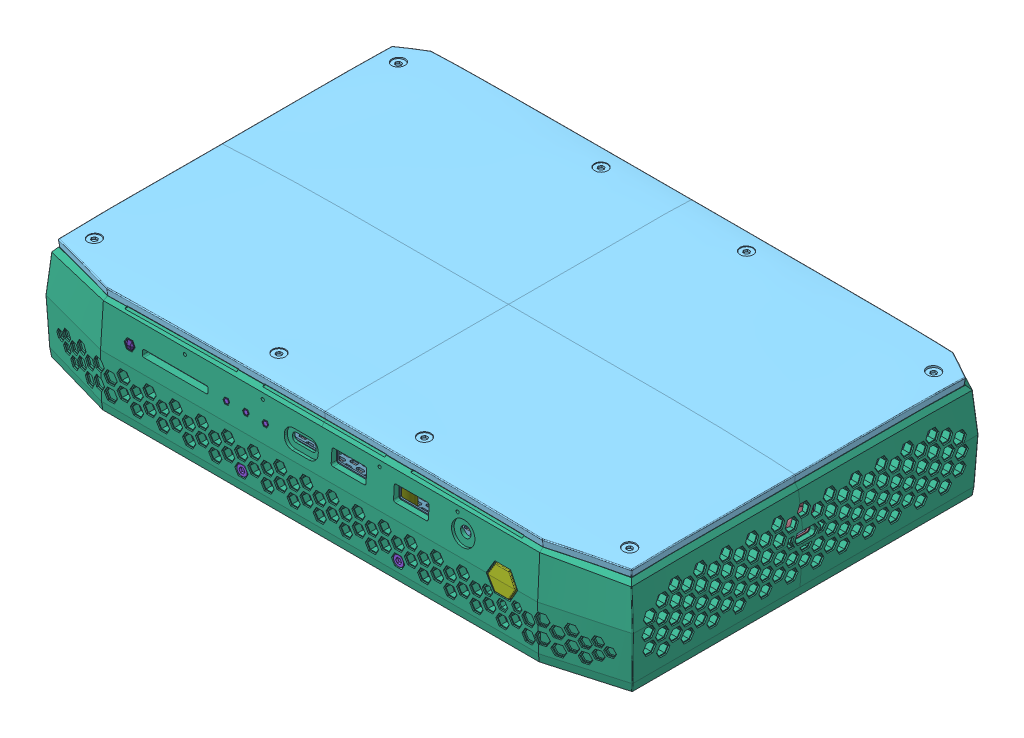
SolidWorks assembly NUC11PHK_Chassis, configuration 默认. Lengths in mm.
Overall size (227.06 46.07 149.29).
158 component instances, 62 part files, 0 mates.
Components (placement in the parent):
- NUC11PHK_Chassis.stp-1: NUC11PHK_Chassis.stp [默认] at origin size (227.06 46.07 149.29)
  - PHANTOM_TOP_ASSEMBLY_20210107_A_ASM.stp-1: PHANTOM_TOP_ASSEMBLY_20210107_A_ASM.stp [默认] at origin size (227.06 46.07 149.29)
    - 00_PH2_TOP_ASSEMBLY_1_ASM_1_ASM.stp-1: 00_PH2_TOP_ASSEMBLY_1_ASM_1_ASM.stp [默认] at origin size (227.06 46.07 149.29)
      - PH2_PLACEMENT_ASM_1_ASM_1_ASM.stp-1: PH2_PLACEMENT_ASM_1_ASM_1_ASM.stp [默认] at origin size (216.05 22.71 129.5)
        - PH2_DMIC_ASSY_1_ASM_1_ASM.stp-1: PH2_DMIC_ASSY_1_ASM_1_ASM.stp [默认] at origin size (126.85 6.48 12.79)
          - PH2_DMIC_20200115_NESSIE_ASM_1_.stp-1: PH2_DMIC_20200115_NESSIE_ASM_1_.stp [默认] at origin size (121 5.7 4.3)
          - SCREW_M1_6L25_D45_1_1.stp-1: SCREW_M1_6L25_D45_1_1.stp [默认] at (46.3 34.39 66.2) size (4.5 4.5 3.5)
          - SCREW_M1_6L25_D45_1_1.stp-2: SCREW_M1_6L25_D45_1_1.stp [默认] at (-42 34.39 66.2) size (4.5 4.5 3.5)
          - PH2_DMIC_PCB_1_1.stp-1: PH2_DMIC_PCB_1_1.stp [默认] at origin size (126.85 6.48 10.49)
        - PH2_ANTENNA_ASSY_1_ASM_1_ASM.stp-1: PH2_ANTENNA_ASSY_1_ASM_1_ASM.stp [默认] at origin size (216.05 18.5 8.66)
          - PH_MAIN_1_ASM_1_ASM.stp-1: PH_MAIN_1_ASM_1_ASM.stp [默认] at (81.379 35.3 68.0336) x (0.961262 0 -0.275637) z (0 1 0) size (25.5 1.55 18.5)
            - PH_MAIN_1_1_1.stp-1: PH_MAIN_1_1_1.stp [默认] at origin size (25 0.4 18.5)
            - PH_MAIN_1_2_1.stp-1: PH_MAIN_1_2_1.stp [默认] at origin size (10.5 1.15 1.15)
          - PH_AUX_1_ASM_1_ASM.stp-1: PH_AUX_1_ASM_1_ASM.stp [默认] at (-110.2168 35.3 59.7645) x (0.961262 0 0.275637) z (0 1 0) size (25.5 1.55 18.5)
            - PH_AUX_1_1_1.stp-1: PH_AUX_1_1_1.stp [默认] at origin size (25 0.4 18.5)
            - PH_AUX_1_2_1.stp-1: PH_AUX_1_2_1.stp [默认] at origin size (12.5 1.15 1.15)
        - PH2_BACKLIGHT_MODULE_ASSY_1_ASM_ASM.stp-1: PH2_BACKLIGHT_MODULE_ASSY_1_ASM_ASM.stp [默认] at origin size (166.09 11.72 118.03)
          - PH2_LGF_COVER_ASM_1_ASM_1_ASM.stp-1: PH2_LGF_COVER_ASM_1_ASM_1_ASM.stp [默认] at origin size (164.16 5.51 118.03)
            - PH2_LGF_COVER_1_1.stp-1: PH2_LGF_COVER_1_1.stp [默认] at origin size (164.16 5.51 118.03)
            - PH2_INSERT_NUT_M1_6L1_5_1_1.stp-1: PH2_INSERT_NUT_M1_6L1_5_1_1.stp [默认] at (-75 38 28.25) x (-1 0 0) z (0 0 1) size (2.51 1.65 2.51)
            - PH2_INSERT_NUT_M1_6L1_5_1_1.stp-2: PH2_INSERT_NUT_M1_6L1_5_1_1.stp [默认] at (-75 38 -11.75) x (-1 0 0) z (0 0 1) size (2.51 1.65 2.51)
            - PH2_INSERT_NUT_M1_6L1_5_1_1.stp-3: PH2_INSERT_NUT_M1_6L1_5_1_1.stp [默认] at (-75 38 -52.25) x (-1 0 0) z (0 0 1) size (2.51 1.65 2.51)
          - PH2_LED_FPC_ASSY_1_ASM_1_ASM.stp-1: PH2_LED_FPC_ASSY_1_ASM_1_ASM.stp [默认] at origin size (27.21 10.01 111)
            - PH2_LED_FPC_2_1_1.stp-1: PH2_LED_FPC_2_1_1.stp [默认] at origin size (24.16 9.01 111)
            - LED_8P_177X49_LITE_1_1.stp-1: LED_8P_177X49_LITE_1_1.stp [默认] at (-67.95 36.9 43.25) x (0 0 -1) z (0 1 0) size (4.5 1.26 0.9)
            - LED_8P_177X49_LITE_1_1.stp-2: LED_8P_177X49_LITE_1_1.stp [默认] at (-67.95 36.9 33.25) x (0 0 -1) z (0 1 0) size (4.5 1.26 0.9)
            - LED_8P_177X49_LITE_1_1.stp-3: LED_8P_177X49_LITE_1_1.stp [默认] at (-67.95 36.9 23.25) x (0 0 -1) z (0 1 0) size (4.5 1.26 0.9)
            - LED_8P_177X49_LITE_1_1.stp-4: LED_8P_177X49_LITE_1_1.stp [默认] at (-67.95 36.9 13.25) x (0 0 -1) z (0 1 0) size (4.5 1.26 0.9)
            - LED_8P_177X49_LITE_1_1.stp-5: LED_8P_177X49_LITE_1_1.stp [默认] at (-67.95 36.9 3.25) x (0 0 -1) z (0 1 0) size (4.5 1.26 0.9)
            - LED_8P_177X49_LITE_1_1.stp-6: LED_8P_177X49_LITE_1_1.stp [默认] at (-67.95 36.9 -6.75) x (0 0 -1) z (0 1 0) size (4.5 1.26 0.9)
            - LED_8P_177X49_LITE_1_1.stp-7: LED_8P_177X49_LITE_1_1.stp [默认] at (-67.95 36.9 -16.75) x (0 0 -1) z (0 1 0) size (4.5 1.26 0.9)
            - LED_8P_177X49_LITE_1_1.stp-8: LED_8P_177X49_LITE_1_1.stp [默认] at (-67.95 36.9 -26.75) x (0 0 -1) z (0 1 0) size (4.5 1.26 0.9)
            - LED_8P_177X49_LITE_1_1.stp-9: LED_8P_177X49_LITE_1_1.stp [默认] at (-67.95 36.9 -36.75) x (0 0 -1) z (0 1 0) size (4.5 1.26 0.9)
            - LED_8P_177X49_LITE_1_1.stp-10: LED_8P_177X49_LITE_1_1.stp [默认] at (-67.95 36.9 -46.75) x (0 0 -1) z (0 1 0) size (4.5 1.26 0.9)
            - PH2_FPC_PLATE_1_1_1.stp-1: PH2_FPC_PLATE_1_1_1.stp [默认] at origin size (10.2 0.6 111)
            - PH2_FPC_PLATE_2_1_1.stp-1: PH2_FPC_PLATE_2_1_1.stp [默认] at (-54.6626 127.94 0) x (0 1 0) z (0 0 1) size (7.15 0.6 10.8)
            - PH2_FPC_PLATE_3_1_1.stp-1: PH2_FPC_PLATE_3_1_1.stp [默认] at origin size (10 0.6 17.8)
            - MX_WTOB_1X6P_39_2HD_1_1.stp-1: MX_WTOB_1X6P_39_2HD_1_1.stp [默认] at (-91.5626 29.79 4.75) x (0 0 1) z (-1 0 0) size (8 5.05 2.95)
          - PH2_LOGO_MASK_ASM_1_ASM_1_ASM.stp-1: PH2_LOGO_MASK_ASM_1_ASM_1_ASM.stp [默认] at origin size (100 0.8 100)
            - PH2_LOGO_MASK_1_1.stp-1: PH2_LOGO_MASK_1_1.stp [默认] at origin size (100 0.8 100)
          - PH2_BACKLIGHT_LGF3_1_1.stp-1: PH2_BACKLIGHT_LGF3_1_1.stp [默认] at (60 2.4 9.2) x (-1 0 0) z (0 0 -1) size (133.8 1 111)
          - PH2_LGF_WHITE_MYLAR_1_1.stp-1: PH2_LGF_WHITE_MYLAR_1_1.stp [默认] at origin size (133.8 0.1 111)
      - PH2_ME_ASM_1_ASM_1_ASM.stp-1: PH2_ME_ASM_1_ASM_1_ASM.stp [默认] at origin size (227.06 46.07 149.29)
        - PH2_TOP_COVER_ASM_1_ASM_1_ASM.stp-1: PH2_TOP_COVER_ASM_1_ASM_1_ASM.stp [默认] at origin size (222.64 7.19 149.29)
          - PH2_TOP_COVER_ACCESSORY_ASM_1_A_ASM.stp-1: PH2_TOP_COVER_ACCESSORY_ASM_1_A_ASM.stp [默认] at origin size (212 2.5 74.3)
            - PH2_TOP_COVER_GASKET_1_1.stp-1: PH2_TOP_COVER_GASKET_1_1.stp [默认] at origin size (12.7 2.5 18.5)
            - PH2_TOP_CVR_GASKET_R_1_1.stp-1: PH2_TOP_CVR_GASKET_R_1_1.stp [默认] at origin size (6 0.5 37.5)
            - PH2_TOP_CVR_GASKET_L_1_1.stp-1: PH2_TOP_CVR_GASKET_L_1_1.stp [默认] at origin size (6 0.5 19.5)
            - PH2_TOP_CVR_GSKT_HDR_1_1.stp-1: PH2_TOP_CVR_GSKT_HDR_1_1.stp [默认] at origin size (23 0.5 34)
          - PH2_TOP_COVER_1_1.stp-1: PH2_TOP_COVER_1_1.stp [默认] at origin size (222.64 7.19 149.29)
          - PH2_TOP_COVER_LABEL_1_1.stp-1: PH2_TOP_COVER_LABEL_1_1.stp [默认] at origin size (8 0.1 10)
        - PH2_MB_SHIELD_ASM_1_ASM_1_ASM.stp-1: PH2_MB_SHIELD_ASM_1_ASM_1_ASM.stp [默认] at origin size (219.8 27.7 138.8)
          - PH2_MB_SHIELD_ACCESSORY_1_ASM_1_ASM.stp-1: PH2_MB_SHIELD_ACCESSORY_1_ASM_1_ASM.stp [默认] at origin size (173.7 9 131.8)
            - PHANTOM_MB_GASKET_1_1_1.stp-1: PHANTOM_MB_GASKET_1_1_1.stp [默认] at origin size (9 5.5 5)
            - PHANTOM_MB_GASKET_1_1_1.stp-2: PHANTOM_MB_GASKET_1_1_1.stp [默认] at (-18.5 0 0) size (9 5.5 5)
            - PHANTOM_MB_GASKET_1_1_1.stp-3: PHANTOM_MB_GASKET_1_1_1.stp [默认] at (-43.5 0 0) size (9 5.5 5)
            - PHANTOM_MB_GASKET_1_1_1.stp-4: PHANTOM_MB_GASKET_1_1_1.stp [默认] at (19.85 0 -8) x (-1 0 0) z (0 0 -1) size (9 5.5 5)
            - PHANTOM_MB_GASKET_2_1_1.stp-1: PHANTOM_MB_GASKET_2_1_1.stp [默认] at origin size (20 9 5)
            - PHANTOM_MB_GASKET_3_1_1.stp-1: PHANTOM_MB_GASKET_3_1_1.stp [默认] at origin size (12 7.5 4)
            - PHANTOM_MB_GASKET_3_1_1.stp-2: PHANTOM_MB_GASKET_3_1_1.stp [默认] at (88.92 0 -125) size (12 7.5 4)
            - PHANTOM_MB_GASKET_3_1_1.stp-3: PHANTOM_MB_GASKET_3_1_1.stp [默认] at (-4.63 0 -127.3) size (12 7.5 4)
            - PHANTOM_MB_GASKET_4_1_1.stp-1: PHANTOM_MB_GASKET_4_1_1.stp [默认] at origin size (16 3.5 7.5)
            - PHANTOM_MB_GASKET_5_1_1.stp-1: PHANTOM_MB_GASKET_5_1_1.stp [默认] at origin size (14.5 2 5)
            - PHANTOM_MB_GASKET_5_1_1.stp-2: PHANTOM_MB_GASKET_5_1_1.stp [默认] at (-27 0 0) size (14.5 2 5)
            - PHANTOM_MB_GASKET_5_1_1.stp-3: PHANTOM_MB_GASKET_5_1_1.stp [默认] at (-119.08 0 -0.03) size (14.5 2 5)
            - PHANTOM_MB_GASKET_6_1_1.stp-1: PHANTOM_MB_GASKET_6_1_1.stp [默认] at origin size (9 4.5 3)
          - PH2_MB_SHIELD_1_1.stp-1: PH2_MB_SHIELD_1_1.stp [默认] at origin size (219.8 27.65 138.8)
          - PH2_MB_SHIELD_BKT_R_1_1.stp-1: PH2_MB_SHIELD_BKT_R_1_1.stp [默认] at origin size (27.5 10.7 50)
          - PH2_MB_SHIELD_BKT_L_1_1.stp-1: PH2_MB_SHIELD_BKT_L_1_1.stp [默认] at origin size (33.25 9.6 34.2)
          - PH2_LGF_STANDOFF_2_1_1.stp-1: PH2_LGF_STANDOFF_2_1_1.stp [默认] at (61.5 36.5 54) x (-1 0 0) z (0 1 0) size (6.24 5.4 2.5)
          - PH2_LGF_STANDOFF_2_1_1.stp-2: PH2_LGF_STANDOFF_2_1_1.stp [默认] at (61.5 36.5 -54) x (-1 0 0) z (0 1 0) size (6.24 5.4 2.5)
          - PH2_LGF_STANDOFF_2_1_1.stp-3: PH2_LGF_STANDOFF_2_1_1.stp [默认] at (28 36.5 58.6) x (-1 0 0) z (0 1 0) size (6.24 5.4 2.5)
          - PH2_LGF_STANDOFF_2_1_1.stp-4: PH2_LGF_STANDOFF_2_1_1.stp [默认] at (-28 36.5 58.6) x (-1 0 0) z (0 1 0) size (6.24 5.4 2.5)
          - PH2_LGF_STANDOFF_2_1_1.stp-5: PH2_LGF_STANDOFF_2_1_1.stp [默认] at (28 36.5 -65.39) x (-1 0 0) z (0 1 0) size (6.24 5.4 2.5)
          - PH2_LGF_STANDOFF_2_1_1.stp-6: PH2_LGF_STANDOFF_2_1_1.stp [默认] at (-28 36.5 -65.39) x (-1 0 0) z (0 1 0) size (6.24 5.4 2.5)
        - PH2_MID_FRAME_ASSY_1_ASM_1_ASM.stp-1: PH2_MID_FRAME_ASSY_1_ASM_1_ASM.stp [默认] at origin size (227.06 38.56 148.19)
          - PH2_IR_WINDOW_1_ASM_1_ASM.stp-1: PH2_IR_WINDOW_1_ASM_1_ASM.stp [默认] at origin size (10.5 8.5 3.84)
            - PH2_IR_WINDOW_1_1_1.stp-1: PH2_IR_WINDOW_1_1_1.stp [默认] at origin size (3.52 3.06 3.6)
            - PH2_IR_WINDOW_1_2_1.stp-1: PH2_IR_WINDOW_1_2_1.stp [默认] at origin size (10.5 8.5 0.8)
          - PH2_MID_FRAME_AL-F_GASK-23145_1_ASM.stp-1: PH2_MID_FRAME_AL-F_GASK-23145_1_ASM.stp [默认] at origin size (30.37 17.75 0.6)
            - PH2_MID_FRAME_AL-F_GASK-23152_4_ASM.stp-1: PH2_MID_FRAME_AL-F_GASK-23152_4_ASM.stp [默认] at origin size (30.37 11.79 0.5)
              - PH2_MID_FRAME_AL-F_GASK-23152_3.stp-1: PH2_MID_FRAME_AL-F_GASK-23152_3.stp [默认] at origin size (5.5 6.12 0.5)
              - PH2_MID_FRAME_AL-F_GASK-23152_5.stp-1: PH2_MID_FRAME_AL-F_GASK-23152_5.stp [默认] at origin size (4.52 4.5 0.5)
            - PH2_MID_FRAME_AL_FOIL_1_1.stp-1: PH2_MID_FRAME_AL_FOIL_1_1.stp [默认] at origin size (30.37 17.75 0.1)
          - PH2_MID_FRAME_GASKET_2_1_ASM_1_ASM.stp-1: PH2_MID_FRAME_GASKET_2_1_ASM_1_ASM.stp [默认] at origin size (7.93 1.12 10.01)
            - PH2_MID_FRAME_EMI_TAPE_B_1_1.stp-1: PH2_MID_FRAME_EMI_TAPE_B_1_1.stp [默认] at origin size (7.93 0.12 10.01)
            - PH2_MID_FRAME_EMI_GASKET_B_1_1.stp-1: PH2_MID_FRAME_EMI_GASKET_B_1_1.stp [默认] at origin size (5.55 1 4.08)
          - PH2_MID_FRAME_GASKET_2_1_ASM_1_ASM.stp-2: PH2_MID_FRAME_GASKET_2_1_ASM_1_ASM.stp [默认] at (114.0707 0 55.6557) x (0.615431 0 0.78819) z (-0.78819 0 0.615431) size (7.93 1.12 10.01)
            - PH2_MID_FRAME_EMI_TAPE_B_1_1.stp-1: PH2_MID_FRAME_EMI_TAPE_B_1_1.stp [默认] at origin size (7.93 0.12 10.01)
            - PH2_MID_FRAME_EMI_GASKET_B_1_1.stp-1: PH2_MID_FRAME_EMI_GASKET_B_1_1.stp [默认] at origin size (5.55 1 4.08)
          - PH2_MID_FRAME_1_1.stp-1: PH2_MID_FRAME_1_1.stp [默认] at origin size (227.06 38.56 148.19)
          - PH2_PWR_BUTTON_1_1.stp-1: PH2_PWR_BUTTON_1_1.stp [默认] at origin size (24.47 15.79 5.25)
          - PH2_LENS_1_1.stp-1: PH2_LENS_1_1.stp [默认] at origin size (6.5 6.5 3.4)
          - PH2_LENS_1_1.stp-2: PH2_LENS_1_1.stp [默认] at (-7.5 0 0) size (6.5 6.5 3.4)
          - PH2_LENS_1_1.stp-3: PH2_LENS_1_1.stp [默认] at (-15 0 0) size (6.5 6.5 3.4)
          - PH2_MID_FRAME_NUT_1_1_1.stp-1: PH2_MID_FRAME_NUT_1_1_1.stp [默认] at (103 33.3 -62.39) size (3.4 5 3.4)
          - PH2_MID_FRAME_NUT_1_1_1.stp-2: PH2_MID_FRAME_NUT_1_1_1.stp [默认] at (97.8 33.3 -67) size (3.4 5 3.4)
          - PH2_MID_FRAME_NUT_1_1_1.stp-3: PH2_MID_FRAME_NUT_1_1_1.stp [默认] at (103 33.3 54.62) size (3.4 5 3.4)
          - PH2_MID_FRAME_NUT_1_1_1.stp-4: PH2_MID_FRAME_NUT_1_1_1.stp [默认] at (-103 33.3 54.62) size (3.4 5 3.4)
          - PH2_MID_FRAME_NUT_1_1_1.stp-5: PH2_MID_FRAME_NUT_1_1_1.stp [默认] at (-103.1 33.3 43.2) size (3.4 5 3.4)
          - PH2_MID_FRAME_NUT_1_1_1.stp-6: PH2_MID_FRAME_NUT_1_1_1.stp [默认] at (-96.5 33.3 -53.3) size (3.4 5 3.4)
          - PH2_MID_FRAME_NUT_1_1_1.stp-7: PH2_MID_FRAME_NUT_1_1_1.stp [默认] at (-103 33.3 -62.39) size (3.4 5 3.4)
          - PH2_POWER_BUTTON_SPONGE_2_1_1.stp-1: PH2_POWER_BUTTON_SPONGE_2_1_1.stp [默认] at origin size (23.76 15 1.9)
        - PH2_DMIC_BKT_ASSY_1_ASM_1_ASM.stp-1: PH2_DMIC_BKT_ASSY_1_ASM_1_ASM.stp [默认] at origin size (131.21 8 4.5)
          - PH2_DMIC_BKT_1_1.stp-1: PH2_DMIC_BKT_1_1.stp [默认] at origin size (131.21 8 4.5)
          - PH2_DMIC_BKT_NUT_1_1.stp-1: PH2_DMIC_BKT_NUT_1_1.stp [默认] at (-42 34.39 64.2) size (4 4 2.5)
          - PH2_DMIC_BKT_NUT_1_1.stp-2: PH2_DMIC_BKT_NUT_1_1.stp [默认] at (46.3 34.39 64.2) size (4 4 2.5)
        - PH2_BTM_COVER_ASM_1_ASM_1_ASM.stp-1: PH2_BTM_COVER_ASM_1_ASM_1_ASM.stp [默认] at origin size (219.05 37.9 139.75)
          - PH2_BTM_COVER_ACCESSORY_1_ASM_1_ASM.stp-1: PH2_BTM_COVER_ACCESSORY_1_ASM_1_ASM.stp [默认] at origin size (135 1.2 5)
            - PH2_BTM_COVER_GASKET_1_1.stp-1: PH2_BTM_COVER_GASKET_1_1.stp [默认] at origin size (15 1.2 5)
            - PH2_BTM_COVER_GASKET_1_1.stp-2: PH2_BTM_COVER_GASKET_1_1.stp [默认] at (-60 0 0) size (15 1.2 5)
            - PH2_BTM_COVER_GASKET_1_1.stp-3: PH2_BTM_COVER_GASKET_1_1.stp [默认] at (60 0 0) size (15 1.2 5)
          - PH2_BTM_COVER_1_1.stp-1: PH2_BTM_COVER_1_1.stp [默认] at origin size (219.05 34 139.75)
          - PH2_STANDOFF_MB_3_1_1.stp-1: PH2_STANDOFF_MB_3_1_1.stp [默认] at (-103.7 0 -57) size (7.51 25.3 6.5)
          - PH2_STANDOFF_MB_3_1_1.stp-2: PH2_STANDOFF_MB_3_1_1.stp [默认] at (103.7 0 -57) size (7.51 25.3 6.5)
          - PH2_STANDOFF_MB_2_1_1.stp-1: PH2_STANDOFF_MB_2_1_1.stp [默认] at (96.6 0 56.4) size (7.51 23.7 6.5)
          - PH2_STANDOFF_MB_2_1_1.stp-2: PH2_STANDOFF_MB_2_1_1.stp [默认] at (-96.6 0 56.4) size (7.51 23.7 6.5)
          - PH2_STANDOFF_MB_2_1_1.stp-3: PH2_STANDOFF_MB_2_1_1.stp [默认] at (22.05 0 59) size (7.51 23.7 6.5)
          - PH2_STANDOFF_FAN2_1_1.stp-1: PH2_STANDOFF_FAN2_1_1.stp [默认] at (-99.94 0 49.49) size (4.8 9.6 4.8)
          - PH2_STANDOFF_FAN2_1_1.stp-2: PH2_STANDOFF_FAN2_1_1.stp [默认] at (12.34 0 53) size (4.8 9.6 4.8)
          - PH2_STANDOFF_FAN1_1_1.stp-1: PH2_STANDOFF_FAN1_1_1.stp [默认] at (100.43 0 49.49) size (5.3 7.1 5.3)
          - PH2_STANDOFF_FAN1_1_1.stp-2: PH2_STANDOFF_FAN1_1_1.stp [默认] at (102.13 0 -0.92) size (5.3 7.1 5.3)
          - PH2_STANDOFF_FAN1_1_1.stp-3: PH2_STANDOFF_FAN1_1_1.stp [默认] at (-101.64 0 -0.92) size (5.3 7.1 5.3)
          - PH2_STANDOFF_FAN1_1_1.stp-4: PH2_STANDOFF_FAN1_1_1.stp [默认] at (-11.86 0 53) size (5.3 7.1 5.3)
          - PH2_VESA_STANDOFF_1_1.stp-1: PH2_VESA_STANDOFF_1_1.stp [默认] at (0 0 45.65) x (-1 0 0) z (0 1 0) size (6.7 7.74 3.1)
          - PH2_VESA_STANDOFF_1_1.stp-2: PH2_VESA_STANDOFF_1_1.stp [默认] at (0 0 -48.5) x (-1 0 0) z (0 1 0) size (6.7 7.74 3.1)
          - PH2_VESA_STANDOFF_1_1.stp-3: PH2_VESA_STANDOFF_1_1.stp [默认] at (-109.5 20.35 -47.87) x (0 1 0) z (1 0 0) size (6.7 7.74 3.1)
          - PH2_VESA_STANDOFF_1_1.stp-4: PH2_VESA_STANDOFF_1_1.stp [默认] at (-109.5 20.35 41.87) x (0 1 0) z (1 0 0) size (6.7 7.74 3.1)
          - PH2_BTM_M16_NUT_1_1.stp-1: PH2_BTM_M16_NUT_1_1.stp [默认] at (32.17 6.04 -71) size (4 4 1.2)
          - PH2_BTM_M16_NUT_1_1.stp-2: PH2_BTM_M16_NUT_1_1.stp [默认] at (-32.17 6.04 -71) size (4 4 1.2)
          - PH2_BTM_M16_NUT_1_1.stp-3: PH2_BTM_M16_NUT_1_1.stp [默认] at (30.15 6.88 67.5) x (-1 0 0) z (0 0 -1) size (4 4 1.2)
          - PH2_BTM_M16_NUT_1_1.stp-4: PH2_BTM_M16_NUT_1_1.stp [默认] at (-30.15 6.88 67.5) x (-1 0 0) z (0 0 -1) size (4 4 1.2)
          - PH2_RUBBER_FOOT_REAR_1_1.stp-1: PH2_RUBBER_FOOT_REAR_1_1.stp [默认] at (0 0.1 0) size (173.19 13.6 10.77)
          - PH2_RUBBER_FOOT_FRONT_1_1.stp-1: PH2_RUBBER_FOOT_FRONT_1_1.stp [默认] at (0 0.1 0) size (173.7 13.6 10.69)
        - PH2_SCREW_ASSY_1_ASM_1_ASM.stp-1: PH2_SCREW_ASSY_1_ASM_1_ASM.stp [默认] at origin size (211.9 36.86 144.9)
          - PH2_TOP_SCREW_1_1.stp-1: PH2_TOP_SCREW_1_1.stp [默认] at (196.3 25.5 101.42) size (4.8 6.08 4.8)
          - PH2_TOP_SCREW_1_1.stp-2: PH2_TOP_SCREW_1_1.stp [默认] at (196.3 25.5 -15.59) size (4.8 6.08 4.8)
          - PH2_TOP_SCREW_1_1.stp-3: PH2_TOP_SCREW_1_1.stp [默认] at (121.3 26.8 -18.59) size (4.8 6.08 4.8)
          - PH2_TOP_SCREW_1_1.stp-4: PH2_TOP_SCREW_1_1.stp [默认] at (65.3 26.8 -18.59) size (4.8 6.08 4.8)
          - PH2_TOP_SCREW_1_1.stp-5: PH2_TOP_SCREW_1_1.stp [默认] at (-9.7 25.5 -15.59) size (4.8 6.08 4.8)
          - PH2_TOP_SCREW_1_1.stp-6: PH2_TOP_SCREW_1_1.stp [默认] at (65.3 26.8 105.4) size (4.8 6.08 4.8)
          - PH2_TOP_SCREW_1_1.stp-7: PH2_TOP_SCREW_1_1.stp [默认] at (-9.7 25.5 101.42) size (4.8 6.08 4.8)
          - PH2_TOP_SCREW_1_1.stp-8: PH2_TOP_SCREW_1_1.stp [默认] at (121.3 26.8 105.4) size (4.8 6.08 4.8)
          - PH2_SCREW_M2H70_D45_1_1.stp-1: PH2_SCREW_M2H70_D45_1_1.stp [默认] at (103.7 28.4 -57) x (-1 0 0) z (0 1 0) size (4.5 4.5 7.8)
          - PH2_SCREW_M2H70_D45_1_1.stp-2: PH2_SCREW_M2H70_D45_1_1.stp [默认] at (96.6 28.4 56.4) x (-1 0 0) z (0 1 0) size (4.5 4.5 7.8)
          - PH2_SCREW_M2H70_D45_1_1.stp-3: PH2_SCREW_M2H70_D45_1_1.stp [默认] at (-96.6 28.4 56.4) x (-1 0 0) z (0 1 0) size (4.5 4.5 7.8)
          - PH2_SCREW_M2H70_D45_1_1.stp-4: PH2_SCREW_M2H70_D45_1_1.stp [默认] at (-103.7 28.4 -57) x (-1 0 0) z (0 1 0) size (4.5 4.5 7.8)
          - SCREW_M1_6L25_D45_1_1.stp-1: SCREW_M1_6L25_D45_1_1.stp [默认] at (-42 34.39 66.2) size (4.5 4.5 3.5)
          - SCREW_M1_6L25_D45_1_1.stp-2: SCREW_M1_6L25_D45_1_1.stp [默认] at (46.3 34.39 66.2) size (4.5 4.5 3.5)
          - SCREW_M2H30_D50_1_1.stp-1: SCREW_M2H30_D50_1_1.stp [默认] at (-103.1 36.8 43.2) x (-1 0 0) z (0 1 0) size (5 5 3.8)
          - SCREW_M2H30_D50_1_1.stp-2: SCREW_M2H30_D50_1_1.stp [默认] at (-96.5 36.8 -53.3) x (-1 0 0) z (0 1 0) size (5 5 3.8)
          - SCREW_M2H30_D50_1_1.stp-3: SCREW_M2H30_D50_1_1.stp [默认] at (97.8 36.8 -67) x (-1 0 0) z (0 1 0) size (5 5 3.8)
          - SCREW_M2H30_D50_1_1.stp-4: SCREW_M2H30_D50_1_1.stp [默认] at (-1.02 36.8 -67.1) x (-1 0 0) z (0 1 0) size (5 5 3.8)
          - SCREW_M2H30_D50_1_1.stp-5: SCREW_M2H30_D50_1_1.stp [默认] at (22.05 36.8 59) x (-1 0 0) z (0 1 0) size (5 5 3.8)
          - SCREW_M1_6_L23_D40_ALLEN_HEAD_1.stp-1: SCREW_M1_6_L23_D40_ALLEN_HEAD_1.stp [默认] at (-30.15 6.8846 69.15) size (4.2 4.2 3.85)
          - SCREW_M1_6_L23_D40_ALLEN_HEAD_1.stp-2: SCREW_M1_6_L23_D40_ALLEN_HEAD_1.stp [默认] at (30.15 6.8846 69.15) size (4.2 4.2 3.85)
          - SCREW_M1_6_L23_D40_ALLEN_HEAD_1.stp-3: SCREW_M1_6_L23_D40_ALLEN_HEAD_1.stp [默认] at (32.17 6.0417 -72.65) x (-1 0 0) z (0 0 -1) size (4.2 4.2 3.85)
          - SCREW_M1_6_L23_D40_ALLEN_HEAD_1.stp-4: SCREW_M1_6_L23_D40_ALLEN_HEAD_1.stp [默认] at (-32.17 6.0417 -72.65) x (-1 0 0) z (0 0 -1) size (4.2 4.2 3.85)
